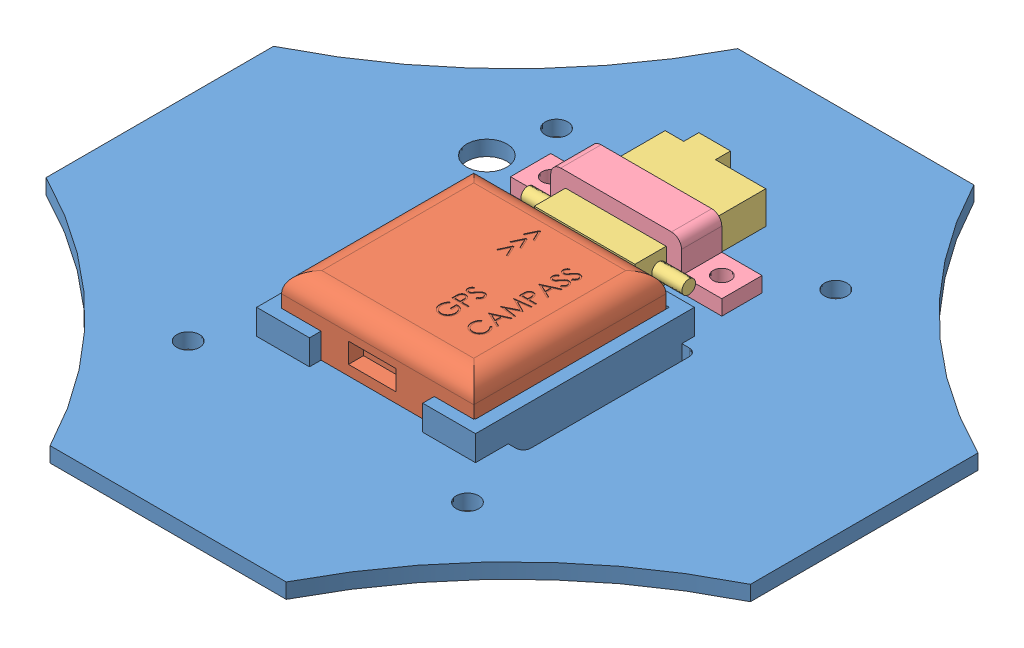
SolidWorks assembly top-layer-assembly, configuration Default. Lengths in mm.
Overall size (140 14.5 140).
4 component instances, 4 part files, 8 mates.
Components (placement in the parent):
- pixfalcon_acc_board-1: pixfalcon_acc_board [Default] at (23.7698 39.6834 65.9451) size (140 7 140)
- pixfalcon_GPS-1: pixfalcon_GPS [Default] at (23.7698 42.6834 73.5451) x (0 0 -1) z (1 0 0) size (38.2 11.5 38.2)
- spectrum-receiver-1: spectrum-receiver [Default] at (23.7023 42.6834 38.4451) size (32 6.5 29)
- spectrum-cover-1: spectrum-cover [Default] at (23.7698 42.6834 37.2451) size (42 9.5 8)
Mates (geometry in assembly coordinates):
- Distance3: distance = 0.5 mm anti-aligned: plane of pixfalcon_acc_board-1 through (4.5198 46.6834 53.9451) normal (0 0 1); plane of pixfalcon_GPS-1 through (4.6698 54.1834 54.4451) normal (0 0 -1)
- Coincident2: coincident anti-aligned: plane of pixfalcon_acc_board-1 through (23.7698 42.6834 65.9451) normal (0 1 0); plane of pixfalcon_GPS-1 through (23.7698 42.6834 73.5451) normal (0 -1 0)
- Distance2: distance = 0.15 mm anti-aligned: plane of pixfalcon_GPS-1 through (4.6698 54.1834 92.6451) normal (-1 0 0); plane of pixfalcon_acc_board-1 through (4.5198 46.6834 53.9451) normal (1 0 0)
- Coincident5: coincident anti-aligned: plane of pixfalcon_acc_board-1 through (23.7698 42.6834 65.9451) normal (0 1 0); plane of spectrum-receiver-1 through (23.7023 42.6834 38.4451) normal (0 -1 0)
- Coincident6: coincident anti-aligned: plane of pixfalcon_acc_board-1 through (2.0198 46.6834 51.4451) normal (0 0 -1); plane of spectrum-receiver-1 through (13.7023 49.1834 51.4451) normal (0 0 1)
- Coincident7: coincident anti-aligned: plane of pixfalcon_acc_board-1 through (23.7698 42.6834 65.9451) normal (0 1 0); plane of spectrum-cover-1 through (44.7698 42.6834 45.2451) normal (0 -1 0)
- Concentric4: concentric aligned: circle of pixfalcon_acc_board-1; circle of spectrum-cover-1
- Concentric5: concentric aligned: circle of pixfalcon_acc_board-1; circle of spectrum-cover-1
